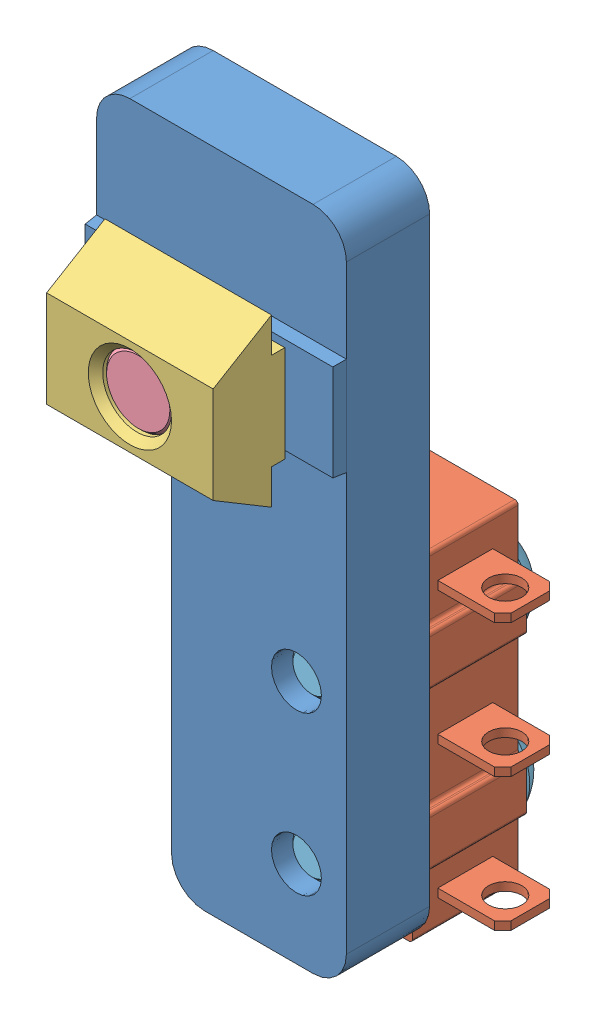
SolidWorks assembly X_Limit_Switch, configuration Default. Lengths in mm.
Overall size (18.3 40.06 18.18).
6 component instances, 5 part files, 11 mates.
Components (placement in the parent):
- XY_LimitSwitch_Mount_B-1: XY_LimitSwitch_Mount_B [Default] at origin size (15 40 5.75)
- Micro Switch Button-1: Micro Switch Button [Default] at (9.6 -29.2 -2.7391) x (0 0 1) z (0 -1 0) size (6.75 16.71 19.86)
- HNTTSN5-5-1: HNTTSN5-5 [Default] at (7.5 -10 6.2) x (0 0 -1) z (1 0 0) size (4.3 10 10)
- 5mmX10mm_Buttonhead(McMaster_91239A224)-1: 5mmX10mm_Buttonhead(McMaster_91239A224) [91239A224] at (7.5 -10 -2.75) x (-0.923728 -0.383049 0) z (0 0 -1) size (9.5 9.5 13.21)
- 3mmX10mm_Buttonhead(McMaster_94500A223)-1: 3mmX10mm_Buttonhead(McMaster_94500A223) [94500A223] at (12 -25.3 -7.5641) x (-0.735593 -0.677423 0) z (0 0 -1) size (5.7 5.7 11.96)
- 3mmX10mm_Buttonhead(McMaster_94500A223)-2: 3mmX10mm_Buttonhead(McMaster_94500A223) [94500A223] at (12 -34.8 -7.5641) x (-0.941182 -0.337899 0) z (0 0 -1) size (5.7 5.7 11.96)
Mates (geometry in assembly coordinates):
- Concentric1: concentric anti-aligned: cylinder of XY_LimitSwitch_Mount_B-1 through (12 -34.8 5) axis (0 0 -1) radius 1.5; cylinder of Micro Switch Button-1 through (12 -34.8 -5.9141) axis (0 0 1) radius 1.35
- Concentric2: concentric anti-aligned: cylinder of XY_LimitSwitch_Mount_B-1 through (12 -25.3 5) axis (0 0 -1) radius 1.5; cylinder of Micro Switch Button-1 through (12 -25.3 -5.9141) axis (0 0 1) radius 1.35
- Concentric3: concentric anti-aligned: cylinder of Micro Switch Button-1 through (12 -34.8 -5.9141) axis (0 0 1) radius 1.35; cylinder of 3mmX10mm_Buttonhead(McMaster_94500A223)-2 through (12 -34.8 -7.5641) axis (0 0 -1) radius 2.85
- Concentric4: concentric anti-aligned: cylinder of Micro Switch Button-1 through (12 -25.3 -5.9141) axis (0 0 1) radius 1.35; cylinder of 3mmX10mm_Buttonhead(McMaster_94500A223)-1 through (12 -25.3 -7.5641) axis (0 0 -1) radius 2.85
- Coincident1: coincident anti-aligned: plane of Micro Switch Button-1 through (14.2 -20.4 -5.9141) normal (0 0 -1); plane of 3mmX10mm_Buttonhead(McMaster_94500A223)-2 through (12.963 -37.4824 -5.9141) normal (0 0 1)
- Coincident2: coincident anti-aligned: plane of Micro Switch Button-1 through (14.2 -20.4 -5.9141) normal (0 0 -1); plane of 3mmX10mm_Buttonhead(McMaster_94500A223)-1 through (13.9307 -27.3964 -5.9141) normal (0 0 1)
- Concentric5: concentric aligned: cylinder of XY_LimitSwitch_Mount_B-1 through (7.5 -10 5) axis (0 0 -1) radius 2.7; cylinder of 5mmX10mm_Buttonhead(McMaster_91239A224)-1 through (7.5 -10 -2.75) axis (0 0 -1) radius 4.75
- Coincident3: coincident anti-aligned: plane of XY_LimitSwitch_Mount_B-1 through (13 -38 0) normal (0 0 -1); plane of 5mmX10mm_Buttonhead(McMaster_91239A224)-1 through (9.3195 -14.3877 0) normal (0 0 1)
- Concentric6: concentric anti-aligned: cylinder of HNTTSN5-5-1 through (7.5 -10 6.2) axis (0 0 1) radius 2.067; cylinder of 5mmX10mm_Buttonhead(McMaster_91239A224)-1 through (7.5 -10 -2.75) axis (0 0 -1) radius 4.75
- Parallel1: parallel aligned: plane of XY_LimitSwitch_Mount_B-1 through (0 -2 5) normal (-1 0 0); plane of HNTTSN5-5-1 through (2.5 -10 6.2) normal (-1 0 0)
- Distance1: distance = 2 mm anti-aligned: plane of XY_LimitSwitch_Mount_B-1 through (13 -38 5) normal (0 0 1); plane of HNTTSN5-5-1 through (12.5 -15 7) normal (0 0 -1)
